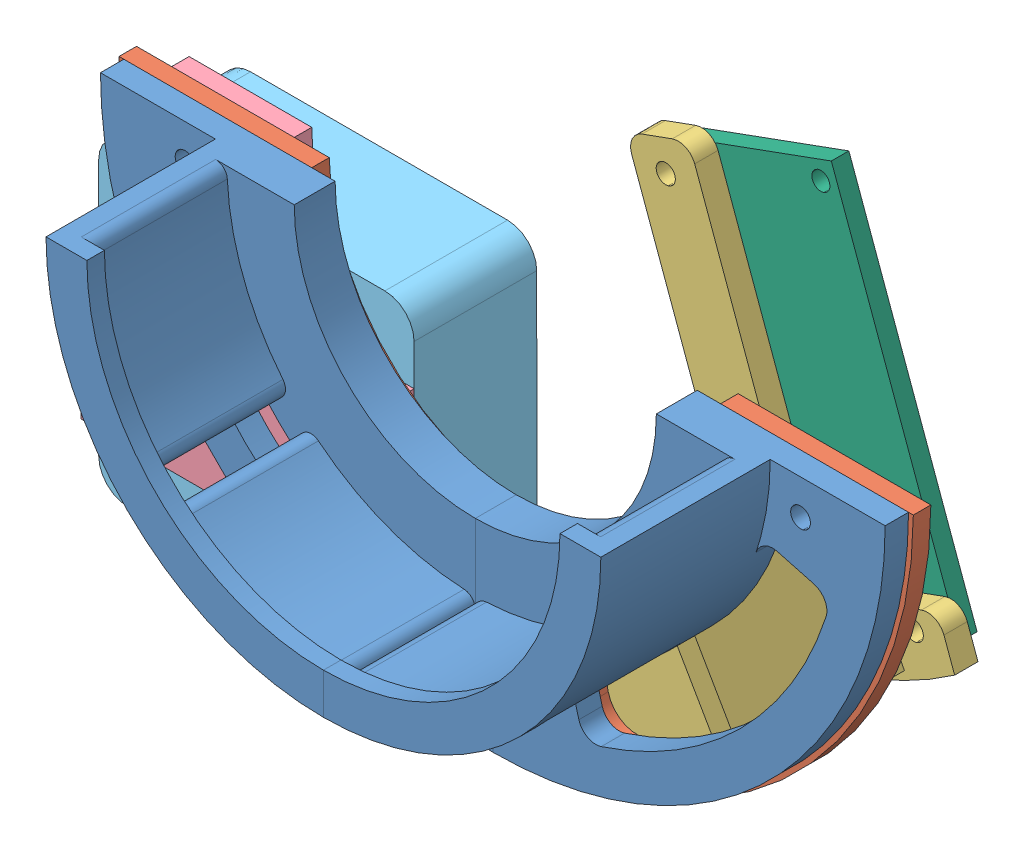
SolidWorks assembly 装配体, configuration 默认. Lengths in mm.
Overall size (161.31 87.4 76).
7 component instances, 6 part files, 18 mates.
Components (placement in the parent):
- 水表直接底座-1: 水表直接底座 [默认] at (-16.0274 32.6265 54.6751) size (67.18 67.18 33)
- 与底部连接件-1: 与底部连接件 [默认] at (-31.606 23.4757 50.6751) x (-1 0 0) z (0 0 -1) size (136 68 3)
- 水表直接底座-2: 水表直接底座 [默认] at (-26.2099 9.4491 54.6751) x (0 -1 0) z (0 0 1) size (67.18 67.18 33)
- 相机架-2: 相机架 [默认] at (-22.7307 0.0713 47.6751) x (-1 0 0) z (0 0 -1) size (57.07 67.51 37)
- M-2: M [默认] at (-55.7483 27.5744 50.6751) x (-0.847984 0.530021 0) z (0 0 -1) size (52.57 70.22 6)
- M5Stack-1: M5Stack [默认] at (-85.7668 -7.9247 23.6751) x (1 0.000195 0) z (0 0 1) size (54 54 21)
- k210-1: k210 [默认] at (-23.3097 -21.8803 7.6751) x (0.939693 0.34202 0) z (0 0 1) size (30 64.2 3)
Mates (geometry in assembly coordinates):
- 重合1: coincident anti-aligned: plane of 水表直接底座-1 through (-32.7074 -4.8709 57.6751) normal (-1 0 0); plane of 水表直接底座-2 through (-32.7074 -4.8709 57.6751) normal (1 0 0)
- 同心1: concentric aligned: cylinder of 水表直接底座-1 through (-32.7074 26.1291 80.6751) axis (0 0 -1) radius 42.5; cylinder of 水表直接底座-2 through (-32.7074 26.1291 80.6751) axis (0 0 -1) radius 42.5
- 重合2: coincident aligned: plane of 水表直接底座-1 through (-32.7074 26.1291 83.6751) normal (0 0 1); plane of 水表直接底座-2 through (-32.7074 26.1291 83.6751) normal (0 0 1)
- 重合3: coincident anti-aligned: plane of 水表直接底座-1 through (-32.7074 26.1291 50.6751) normal (0 0 -1); plane of 与底部连接件-1 through (-32.7074 26.1291 50.6751) normal (0 0 1)
- 同心2: concentric anti-aligned: cylinder of 水表直接底座-1 through (-32.7074 26.1291 80.6751) axis (0 0 -1) radius 42.5; cylinder of 与底部连接件-1 through (-32.7074 26.1291 47.6751) axis (0 0 1) radius 35
- 重合4: coincident aligned: plane of 水表直接底座-1 through (-1.7074 26.1291 57.6751) normal (0 1 0); plane of 与底部连接件-1 through (35.2926 26.1291 47.6751) normal (0 1 0)
- 重合6: coincident anti-aligned: plane of 与底部连接件-1 through (-32.7074 26.1291 47.6751) normal (0 0 -1); plane of 相机架-2 through (-32.7074 26.0989 47.6751) normal (0 0 1)
- 同心6: concentric aligned: circle of 与底部连接件-1; circle of 相机架-2
- 同心8: concentric aligned: circle of 与底部连接件-1; circle of 相机架-2
- 重合9: coincident anti-aligned: plane of 水表直接底座-2 through (-32.7074 26.1291 50.6751) normal (0 0 -1); plane of M-2 through (-32.7074 26.1291 50.6751) normal (0 0 1)
- 重合10: coincident anti-aligned: plane of 与底部连接件-1 through (-72.6577 16.9109 50.6751) normal (0.224834 -0.974397 0); plane of M-2 through (-72.6577 16.9109 47.6751) normal (-0.224834 0.974397 0)
- 同心10: concentric anti-aligned: cylinder of 与底部连接件-1 through (-32.7074 26.1291 50.6751) axis (0 0 -1) radius 41; cylinder of M-2 through (-32.7074 26.1291 47.6751) axis (0 0 1) radius 41
- 重合11: coincident anti-aligned: circle of M-2; cylinder of M5Stack-1 through (-105.1844 -6.885 34.6751) axis (0 0 1) radius 1.6
- 重合12: coincident anti-aligned: circle of M-2; cylinder of M5Stack-1 through (-105.1798 -30.885 34.6751) axis (0 0 1) radius 1.6
- 重合13: coincident anti-aligned: plane of M-2 through (-32.7074 26.1291 44.6751) normal (0 0 -1); plane of M5Stack-1 through (-85.7668 -7.9247 44.6751) normal (0 0 1)
- 重合14: coincident anti-aligned: plane of 相机架-2 through (-22.7307 0.0713 10.6751) normal (0 0 -1); plane of k210-1 through (-23.3097 -21.8803 10.6751) normal (0 0 1)
- 同心11: concentric anti-aligned: cylinder of 相机架-2 through (-43.0945 19.5515 10.6751) axis (0 0 1) radius 1.65; cylinder of k210-1 through (-43.0945 19.5515 10.6751) axis (0 0 -1) radius 1.5542
- 同心12: concentric anti-aligned: cylinder of 相机架-2 through (-0.6363 -26.9301 10.6751) axis (0 0 1) radius 1.65; cylinder of k210-1 through (-0.6363 -26.9301 10.6751) axis (0 0 -1) radius 1.2117
